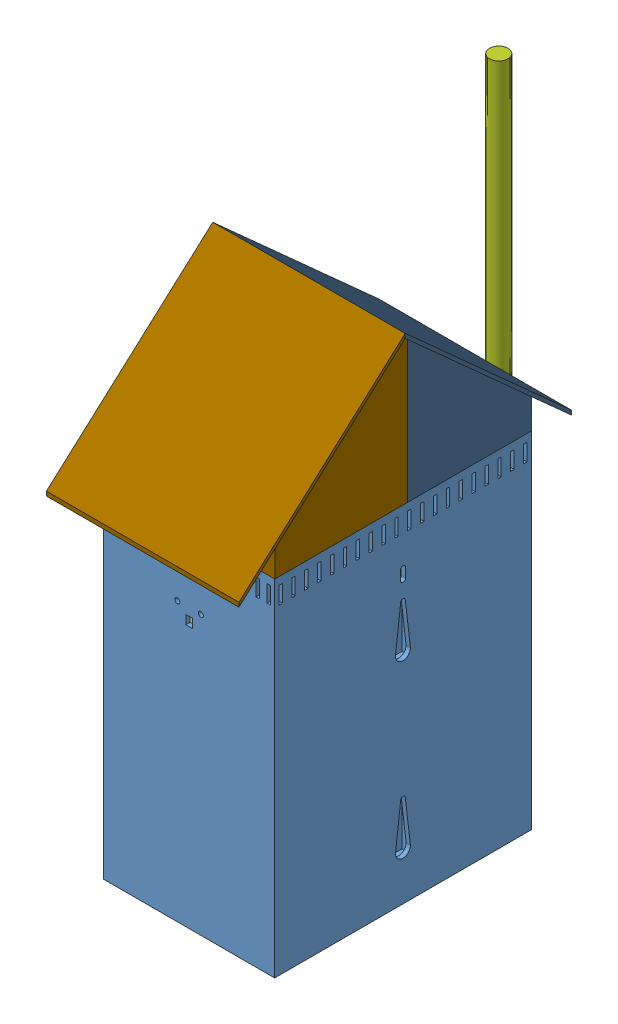
SolidWorks assembly Sensor Housing, configuration Default. Lengths in mm.
Overall size (114.3 358.14 212.48).
69 component instances, 21 part files, 30 mates.
Components (placement in the parent):
- Base-1: Base [Default] at (135.2975 1.996 228.6908) size (101.6 205.74 152.4)
- Door-1: Door [Default] at (48.7972 70.9281 105.6894) x (0 1 0) z (0 0 1) size (203.2 2.54 146.94)
- Gecko-1: Gecko [Default] at (106.8129 3.4585 23.6118) size (2.5 25.4 2.5) (hidden)
- Light sensor-1: Light sensor [Default] at (93.1419 162.4188 223.6108) x (1 0 0) z (0 -1 0) size (19.05 1.4 16.51)
- AC Plug-1: AC Plug [Default] at (118.9484 17.8288 73.2908) x (1 0 0) z (0 -1 0) size (28.3 15.5 16)
- DC Plug-1: DC Plug [Default] at (92.2472 27.17 76.2908) x (-1 0 0) z (0 0 -1) size (57 57 19.5)
- U.FL to SMA Bulkhead-1: U.FL to SMA Bulkhead [Default] at (95.0252 169.636 80.3308) x (0.636486 0.771288 0) z (0 0 -1) size (9 8 14)
- Antenna-1: Antenna [Default] at (95.0252 169.636 76.2908) x (0 1 0) z (-1 0 0) size (196 37 11)
- Light sensor washers-1: Light sensor washers [Default] at (54.7528 1.996 224.8808) size (19.05 5.08 1.27)
- Roof1-1: Roof1 [Default] at (124.8094 220.436 128.6716) x (0 0 1) z (-1 0 0) size (101.32 92.71 114.3)
- Roof2-1: Roof2 [Default] at (124.8094 220.436 128.6716) x (0 0 1) z (-1 0 0) size (101.32 92.71 114.3)
- PCB Holder-1: PCB Holder [Default] at (156.1069 171.6799 151.2208) x (1 0 0) z (0 -1 0) size (11.44 7.81 10.74)
- PCB-2: PCB [Default] at (135.6652 187.236 102.7068) x (0 -1 0) z (-1 0 0) size (170 90 9.05)
  - Raitong_Env_Sensor.step-1: Raitong_Env_Sensor.step [Default] at origin size (170 90 9.05)
    - LED_0603_1608Metric.step-1: LED_0603_1608Metric.step [Default] at (141.7575 55.88 1.6502) size (1.6 0.8 1.1)
      - SOLID.step-1: SOLID.step [Default] at origin size (1.6 0.8 1.1)
    - LED_0603_1608Metric.step-2: LED_0603_1608Metric.step [Default] at (140.97 80.01 1.6502) size (1.6 0.8 1.1)
      - SOLID.step-1: SOLID.step [Default] at origin size (1.6 0.8 1.1)
    - R_0402_1005Metric.step-1: R_0402_1005Metric.step [Default] at (145.0152 80.4986 1.6502) x (-1 0 0) z (0 0 1) size (1 0.5 0.35)
      - SOLID-0.step-1: SOLID-0.step [Default] at origin size (1 0.5 0.35)
    - R_0402_1005Metric.step-2: R_0402_1005Metric.step [Default] at (87.63 43.18 1.6502) size (1 0.5 0.35)
      - SOLID-0.step-1: SOLID-0.step [Default] at origin size (1 0.5 0.35)
    - R_0402_1005Metric.step-3: R_0402_1005Metric.step [Default] at (91.44 43.18 1.6502) x (-1 0 0) z (0 0 1) size (1 0.5 0.35)
      - SOLID-0.step-1: SOLID-0.step [Default] at origin size (1 0.5 0.35)
    - R_0402_1005Metric.step-4: R_0402_1005Metric.step [Default] at (146.05 55.88 1.6502) x (-1 0 0) z (0 0 1) size (1 0.5 0.35)
      - SOLID-0.step-1: SOLID-0.step [Default] at origin size (1 0.5 0.35)
    - PinSocket_1x07_P2.54mm_Vertical_SMD_Pin1Left.step-1: PinSocket_1x07_P2.54mm_Vertical_SMD_Pin1Left.step [Default] at (75.31 34.29 1.6502) size (4.64 17.98 7.4)
      - SOLID-1.step-1: SOLID-1.step [Default] at origin size (4.64 17.98 7.4)
    - PinSocket_1x09_P2.54mm_Vertical_SMD_Pin1Left.step-1: PinSocket_1x09_P2.54mm_Vertical_SMD_Pin1Left.step [Default] at (110.49 76.2 1.6502) size (4.64 23.06 7.4)
      - SOLID-2.step-1: SOLID-2.step [Default] at origin size (4.64 23.06 7.4)
    - PinSocket_1x04_P2.54mm_Vertical_SMD_Pin1Left.step-1: PinSocket_1x04_P2.54mm_Vertical_SMD_Pin1Left.step [Default] at (115.95 30.48 1.6502) size (4.64 10.36 7.4)
      - SOLID-3.step-1: SOLID-3.step [Default] at origin size (4.64 10.36 7.4)
    - PinSocket_1x04_P2.54mm_Vertical_SMD_Pin1Left.step-2: PinSocket_1x04_P2.54mm_Vertical_SMD_Pin1Left.step [Default] at (88.9 30.48 1.6502) size (4.64 10.36 7.4)
      - SOLID-3.step-1: SOLID-3.step [Default] at origin size (4.64 10.36 7.4)
    - PinSocket_1x05_P2.54mm_Vertical_SMD_Pin1Left.step-1: PinSocket_1x05_P2.54mm_Vertical_SMD_Pin1Left.step [Default] at (62.23 31.75 1.6502) size (4.64 12.9 7.4)
      - SOLID-4.step-1: SOLID-4.step [Default] at origin size (4.64 12.9 7.4)
    - PinSocket_1x07_P2.54mm_Vertical_SMD_Pin1Left.step-2: PinSocket_1x07_P2.54mm_Vertical_SMD_Pin1Left.step [Default] at (93.98 73.66 1.6502) size (4.64 17.98 7.4)
      - SOLID-1.step-1: SOLID-1.step [Default] at origin size (4.64 17.98 7.4)
    - C_0402_1005Metric.step-1: C_0402_1005Metric.step [Default] at (149.225 86.36 1.6502) x (-1 0 0) z (0 0 1) size (1 0.5 0.5)
      - SOLID-5.step-1: SOLID-5.step [Default] at origin size (1 0.5 0.5)
    - C_0402_1005Metric.step-2: C_0402_1005Metric.step [Default] at (161.14 82.55 1.6502) size (1 0.5 0.5)
      - SOLID-5.step-1: SOLID-5.step [Default] at origin size (1 0.5 0.5)
    - C_0402_1005Metric.step-3: C_0402_1005Metric.step [Default] at (175.26 86.36 1.6502) size (1 0.5 0.5)
      - SOLID-5.step-1: SOLID-5.step [Default] at origin size (1 0.5 0.5)
    - C_0402_1005Metric.step-4: C_0402_1005Metric.step [Default] at (147.955 66.04 1.6502) size (1 0.5 0.5)
      - SOLID-5.step-1: SOLID-5.step [Default] at origin size (1 0.5 0.5)
    - C_0402_1005Metric.step-5: C_0402_1005Metric.step [Default] at (160.02 62.865 1.6502) x (-1 0 0) z (0 0 1) size (1 0.5 0.5)
      - SOLID-5.step-1: SOLID-5.step [Default] at origin size (1 0.5 0.5)
    - C_0402_1005Metric.step-6: C_0402_1005Metric.step [Default] at (174.625 67.31 1.6502) size (1 0.5 0.5)
      - SOLID-5.step-1: SOLID-5.step [Default] at origin size (1 0.5 0.5)
    - L_0402_1005Metric.step-1: L_0402_1005Metric.step [Default] at (167.155 86.36 1.6502) size (1 0.5 0.5)
      - SOLID-6.step-1: SOLID-6.step [Default] at origin size (1 0.5 0.5)
    - L_0402_1005Metric.step-2: L_0402_1005Metric.step [Default] at (165.1 66.675 1.6502) size (1 0.5 0.5)
      - SOLID-6.step-1: SOLID-6.step [Default] at origin size (1 0.5 0.5)
    - R_0402_1005Metric.step-5: R_0402_1005Metric.step [Default] at (142.24 86.36 1.6502) x (-1 0 0) z (0 0 1) size (1 0.5 0.35)
      - SOLID-0.step-1: SOLID-0.step [Default] at origin size (1 0.5 0.35)
    - R_0402_1005Metric.step-6: R_0402_1005Metric.step [Default] at (161.29 86.36 1.6502) x (-1 0 0) z (0 0 1) size (1 0.5 0.35)
      - SOLID-0.step-1: SOLID-0.step [Default] at origin size (1 0.5 0.35)
    - R_0402_1005Metric.step-7: R_0402_1005Metric.step [Default] at (155.575 86.36 1.6502) x (-1 0 0) z (0 0 1) size (1 0.5 0.35)
      - SOLID-0.step-1: SOLID-0.step [Default] at origin size (1 0.5 0.35)
    - R_0402_1005Metric.step-8: R_0402_1005Metric.step [Default] at (141.455 66.04 1.6502) size (1 0.5 0.35)
      - SOLID-0.step-1: SOLID-0.step [Default] at origin size (1 0.5 0.35)
    - R_0402_1005Metric.step-9: R_0402_1005Metric.step [Default] at (154.305 66.675 1.6502) size (1 0.5 0.35)
      - SOLID-0.step-1: SOLID-0.step [Default] at origin size (1 0.5 0.35)
    - R_0402_1005Metric.step-10: R_0402_1005Metric.step [Default] at (160.17 66.675 1.6502) size (1 0.5 0.35)
      - SOLID-0.step-1: SOLID-0.step [Default] at origin size (1 0.5 0.35)
    - PinSocket_1x04_P2.54mm_Vertical_SMD_Pin1Left.step-3: PinSocket_1x04_P2.54mm_Vertical_SMD_Pin1Left.step [Default] at (101.6 30.48 1.6502) size (4.64 10.36 7.4)
      - SOLID-3.step-1: SOLID-3.step [Default] at origin size (4.64 10.36 7.4)
    - COMPOUND.step-1: COMPOUND.step [Default] at origin size (170 90 1.6)
Mates (geometry in assembly coordinates):
- Coincident1: coincident: plane of Base-1 through (135.2975 4.536 228.6908) normal (0 1 0); plane of Door-1 through (46.2572 4.536 79.2118) normal (0 -1 0)
- Coincident2: coincident: plane of Base-1 through (45.4952 207.736 226.1508) normal (0 0 -1); plane of Door-1 through (46.2572 4.536 226.1508) normal (0 0 1)
- Coincident3: coincident: plane of Base-1 through (48.7972 207.736 226.1508) normal (-1 0 0); plane of Door-1 through (48.7972 70.9281 105.6894) normal (1 0 0)
- Parallel1: parallel: plane of Base-1 through (135.2975 1.996 228.6908) normal (0 -1 0); plane of Gecko-1 through (106.8129 3.4585 23.6118) normal (0 -1 0)
- Coincident34: coincident: plane of Base-1 through (44.2252 4.536 76.2908) normal (0 0 -1); plane of AC Plug-1 through (118.9484 17.8288 76.2908) normal (0 0 1)
- Coincident36: coincident: plane of Base-1 through (114.9352 22.116 88.7908) normal (1 0 0); plane of AC Plug-1 through (114.9352 22.116 88.7908) normal (-1 0 0)
- Coincident37: coincident: plane of Base-1 through (134.4352 9.616 88.7908) normal (0 1 0); plane of AC Plug-1 through (114.9352 9.616 88.7908) normal (0 -1 0)
- Concentric3: concentric: cylinder of Base-1 through (77.6552 31.616 92.7908) axis (0 0 -1) radius 24.2633; cylinder of DC Plug-1 through (77.6552 31.616 92.7908) axis (0 0 -1) radius 24.25
- Coincident38: coincident: circle of Base-1; circle of DC Plug-1
- Concentric4: concentric: circle of Base-1; circle of U.FL to SMA Bulkhead-1
- Coincident48: coincident: plane of Base-1 through (108.8865 207.736 78.8308) normal (0 0 1); plane of U.FL to SMA Bulkhead-1 through (95.0252 169.636 78.8308) normal (0 0 -1)
- Coincident49: coincident: plane of Base-1 through (44.2252 4.536 76.2908) normal (0 0 -1); plane of Antenna-1 through (95.0252 169.636 76.2908) normal (0 0 1)
- Concentric6: concentric: circle of U.FL to SMA Bulkhead-1; circle of Antenna-1
- Parallel8: parallel: plane of Base-1 through (135.2975 4.536 228.6908) normal (0 1 0); plane of Antenna-1 through (95.0252 360.136 76.2908) normal (0 1 0)
- Coincident50: coincident: plane of Base-1 through (50.0672 207.736 226.1508) normal (0 0 -1); plane of Light sensor washers-1 through (102.0102 167.096 226.1508) normal (0 0 1)
- Concentric8: concentric: circle of Light sensor-1; circle of Light sensor washers-1
- Concentric9: concentric: cylinder of Base-1 through (88.0402 167.096 198.9728) axis (0 0 1) radius 1.5; cylinder of Light sensor washers-1 through (88.0402 167.096 226.1508) axis (0 0 -1) radius 1.905
- Coincident56: coincident: plane of Light sensor-1 through (93.1419 162.4188 224.8808) normal (0 0 1); plane of Light sensor washers-1 through (102.0102 167.096 224.8808) normal (0 0 -1)
- Concentric10: concentric: circle of Light sensor-1; circle of Light sensor washers-1
- Coincident58: coincident: plane of Roof1-1 through (45.7769 294.096 150.4508) normal (1 0 0); plane of Roof2-1 through (45.7769 294.096 150.4508) normal (-1 0 0)
- Coincident59: coincident: plane of Roof1-1 through (124.8094 220.436 152.9908) normal (0 0 -1); plane of Roof2-1 through (124.8094 220.436 152.9908) normal (0 0 1)
- Coincident60: coincident: line of Roof1-1 through (147.6743 296.636 152.9908) axis (-1 0 0); line of Roof2-1 through (147.6743 296.636 152.9908) axis (-1 0 0)
- Coincident62: coincident: plane of Base-1 through (50.0672 207.736 78.8308) normal (1 0 0); plane of Roof2-1 through (50.0672 203.926 226.1508) normal (-1 0 0)
- Coincident63: coincident: plane of Base-1 through (50.0672 207.736 226.1508) normal (0 0 -1); plane of Roof1-1 through (142.2062 203.926 226.1508) normal (0 0 1)
- Coincident64: coincident: plane of Base-1 through (135.2975 207.736 228.6908) normal (0 1 0); plane of Roof2-1 through (124.8094 207.736 128.6716) normal (0 -1 0)
- Coincident69: coincident: plane of Base-1 through (143.2852 207.736 190.0828) normal (-1 0 0); plane of PCB Holder-1 through (143.2852 171.6799 151.2208) normal (1 0 0)
- Slot2: slot: cylinder of Base-1 through (142.8252 168.874 152.4908) axis (1 0 0) radius 1.5; cylinder of PCB Holder-1 through (141.2852 169.0943 152.4908) axis (1 0 0) radius 2.75; cylinder of Base-1 through (142.8252 174.462 152.4908) axis (1 0 0) radius 1.5
- Coincident70: coincident: plane of Base-1 through (135.6652 1.996 228.6908) normal (-1 0 0); plane of PCB-2/Raitong_Env_Sensor.step-1/COMPOUND.step-1 through (135.6652 89.536 152.9568) normal (1 0 0)
- Coincident71: coincident: plane of Base-1 through (135.2975 4.536 228.6908) normal (0 1 0); plane of PCB-2/Raitong_Env_Sensor.step-1/COMPOUND.step-1 through (135.6652 4.536 197.9568) normal (0 -1 0)
- Coincident72: coincident: plane of Base-1 through (135.6652 9.616 197.9568) normal (0 0 -1); plane of PCB-2/Raitong_Env_Sensor.step-1/COMPOUND.step-1 through (135.6652 174.536 197.9568) normal (0 0 1)
